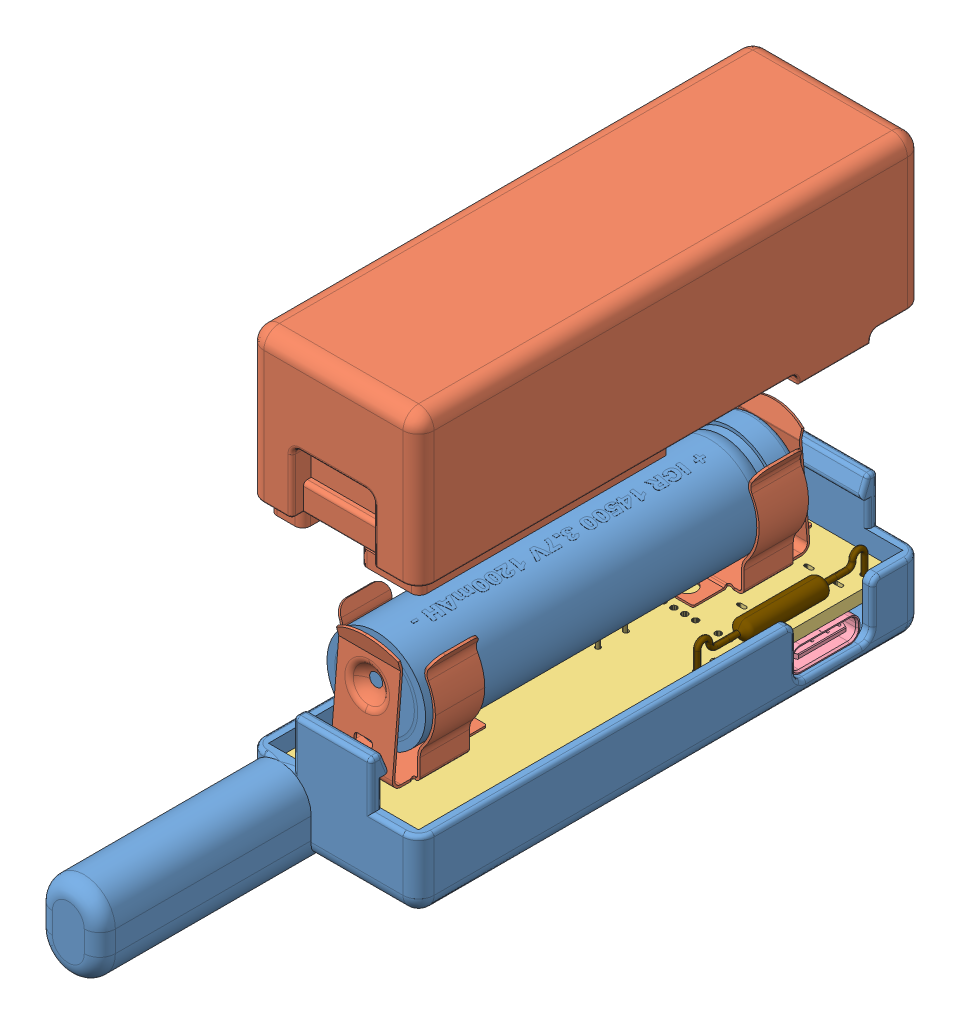
SolidWorks assembly Assem1, configuration Default. Lengths in mm.
Overall size (21.9 57.63 92.1).
106 component instances, 21 part files, 6 mates.
Components (placement in the parent):
- MailBoxGuard_Full_Size_Front_433_868_915-1: MailBoxGuard_Full_Size_Front_433_868_915 [Default] at (-14.6138 29.4677 86.179) size (21.9 16.85 92.1)
- MailBoxGuard_Full_Size_Back_433_868_915-1: MailBoxGuard_Full_Size_Back_433_868_915 [Default] at (-14.6138 81.2445 86.179) x (-1 0 0) z (0 0 1) size (21.9 21 64.9)
- MailBox_Guard_PCB.step-1: MailBox_Guard_PCB.step [Default] at (-22.3128 34.5477 64.4772) x (1 0 0) z (0 -1 0) size (19.9 77.28 23.81)
  - C_0603_1608Metric.step-1: C_0603_1608Metric.step [Default] at (9.97 33.512 1.63) size (1.6 0.8 0.8)
    - SOLID.step-1: SOLID.step [Default] at origin size (1.6 0.8 0.8)
  - C_0603_1608Metric.step-2: C_0603_1608Metric.step [Default] at (3.175 -0.651 1.63) x (0 1 0) z (0 0 1) size (1.6 0.8 0.8)
    - SOLID.step-1: SOLID.step [Default] at origin size (1.6 0.8 0.8)
  - UJC-HP-3-SMT-TR.step-1: UJC-HP-3-SMT-TR.step [Default] at (11.27 0.873 1.63) x (0 1 0) z (1 0 0) size (8.94 4.26 6.9)
    - COMPOUND.step-1: COMPOUND.step [Default] at origin size (8.94 4.26 6.9)
  - SOT-23.step-1: SOT-23.step [Default] at (14.732 18.907 1.63) x (0 1 0) z (0 0 1) size (2.5 3 1.2)
    - SOLID-0.step-1: SOLID-0.step [Default] at origin size (2.5 3 1.2)
  - D_SOD-323.step-1: D_SOD-323.step [Default] at (9.398 25.622 1.63) x (0 1 0) z (0 0 1) size (2.5 1.25 1.1)
    - SOLID-1.step-1: SOLID-1.step [Default] at origin size (2.5 1.25 1.1)
  - SOIJ-8_5.3x5.3mm_P1.27mm.step-1: SOIJ-8_5.3x5.3mm_P1.27mm.step [Default] at (6.985 0.873 1.63) x (0 -1 0) z (0 0 1) size (6.35 5.3 2.01)
    - SOLID-2.step-1: SOLID-2.step [Default] at origin size (6.35 5.3 2.01)
  - HTSOP-8-1EP_3.9x4.9mm_P1.27mm_EP2.4x3.2mm.step-1: HTSOP-8-1EP_3.9x4.9mm_P1.27mm_EP2.4x3.2mm.step [Default] at (6.985 0.873 1.63) x (0 -1 0) z (0 0 1) size (6.3 4.9 1.1)
    - SOLID-3.step-1: SOLID-3.step [Default] at origin size (6.3 4.9 1.1)
  - SOT-23.step-2: SOT-23.step [Default] at (6.415 24.3219 1.63) x (-1 0 0) z (0 0 1) size (2.5 3 1.2)
    - SOLID-0.step-1: SOLID-0.step [Default] at origin size (2.5 3 1.2)
  - D_SOD-323.step-2: D_SOD-323.step [Default] at (15.494 25.638 1.63) x (0 -1 0) z (0 0 1) size (2.5 1.25 1.1)
    - SOLID-1.step-1: SOLID-1.step [Default] at origin size (2.5 1.25 1.1)
  - R_0603_1608Metric.step-1: R_0603_1608Metric.step [Default] at (3.81 28.94 1.63) x (0 1 0) z (0 0 1) size (1.6 0.8 0.45)
    - SOLID-4.step-1: SOLID-4.step [Default] at origin size (1.6 0.8 0.45)
  - C_1206_3216Metric.step-1: C_1206_3216Metric.step [Default] at (1.778 32.037 1.63) x (0 -1 0) z (0 0 1) size (3.2 1.6 1.6)
    - SOLID-5.step-1: SOLID-5.step [Default] at origin size (3.2 1.6 1.6)
  - R_0603_1608Metric.step-2: R_0603_1608Metric.step [Default] at (11.43 22.463 1.63) x (0 -1 0) z (0 0 1) size (1.6 0.8 0.45)
    - SOLID-4.step-1: SOLID-4.step [Default] at origin size (1.6 0.8 0.45)
  - C_0603_1608Metric.step-3: C_0603_1608Metric.step [Default] at (-0.254 25.892 1.63) x (0 1 0) z (0 0 1) size (1.6 0.8 0.8)
    - SOLID.step-1: SOLID.step [Default] at origin size (1.6 0.8 0.8)
  - R_0603_1608Metric.step-3: R_0603_1608Metric.step [Default] at (11.557 -5.604 1.63) x (-1 0 0) z (0 0 1) size (1.6 0.8 0.45)
    - SOLID-4.step-1: SOLID-4.step [Default] at origin size (1.6 0.8 0.45)
  - C_0603_1608Metric.step-4: C_0603_1608Metric.step [Default] at (1.778 27.797 1.63) x (0 1 0) z (0 0 1) size (1.6 0.8 0.8)
    - SOLID.step-1: SOLID.step [Default] at origin size (1.6 0.8 0.8)
  - VQFN-20-1EP_3x3mm_P0.45mm_EP1.55x1.55mm.step-1: VQFN-20-1EP_3x3mm_P0.45mm_EP1.55x1.55mm.step [Default] at (14.351 30.375 1.63) x (0 -1 0) z (0 0 1) size (3 3 0.6)
    - SOLID-6.step-1: SOLID-6.step [Default] at origin size (3 3 0.6)
  - R_0603_1608Metric.step-4: R_0603_1608Metric.step [Default] at (9.97 28.94 1.63) x (-1 0 0) z (0 0 1) size (1.6 0.8 0.45)
    - SOLID-4.step-1: SOLID-4.step [Default] at origin size (1.6 0.8 0.45)
  - R_0603_1608Metric.step-5: R_0603_1608Metric.step [Default] at (9.97 31.988 1.63) size (1.6 0.8 0.45)
    - SOLID-4.step-1: SOLID-4.step [Default] at origin size (1.6 0.8 0.45)
  - R_0603_1608Metric.step-6: R_0603_1608Metric.step [Default] at (6.604 -3.953 1.63) size (1.6 0.8 0.45)
    - SOLID-4.step-1: SOLID-4.step [Default] at origin size (1.6 0.8 0.45)
  - R_0603_1608Metric.step-7: R_0603_1608Metric.step [Default] at (9.398 22.463 1.63) x (0 1 0) z (0 0 1) size (1.6 0.8 0.45)
    - SOLID-4.step-1: SOLID-4.step [Default] at origin size (1.6 0.8 0.45)
  - SOT-23.step-3: SOT-23.step [Default] at (2.4919 24.3211 1.63) size (2.5 3 1.2)
    - SOLID-0.step-1: SOLID-0.step [Default] at origin size (2.5 3 1.2)
  - SOT-23.step-4: SOT-23.step [Default] at (11.811 15.224 1.63) size (2.5 3 1.2)
    - SOLID-0.step-1: SOLID-0.step [Default] at origin size (2.5 3 1.2)
  - D_SOD-323.step-3: D_SOD-323.step [Default] at (13.462 25.638 1.63) x (0 -1 0) z (0 0 1) size (2.5 1.25 1.1)
    - SOLID-1.step-1: SOLID-1.step [Default] at origin size (2.5 1.25 1.1)
  - AS312 AM312 PIR.step-1: AS312 AM312 PIR.step [Default] at (4.826 17.248 1.63) x (0.707107 -0.707107 0) z (0 0 1) size (9.98 9.98 6.93)
    - SOLID-7.step-1: SOLID-7.step [Default] at origin size (9.98 9.98 6.93)
  - R_0603_1608Metric.step-8: R_0603_1608Metric.step [Default] at (11.43 17.764 1.63) x (-1 0 0) z (0 0 1) size (1.6 0.8 0.45)
    - SOLID-4.step-1: SOLID-4.step [Default] at origin size (1.6 0.8 0.45)
  - R_0603_1608Metric.step-9: R_0603_1608Metric.step [Default] at (13.462 22.463 1.63) x (0 -1 0) z (0 0 1) size (1.6 0.8 0.45)
    - SOLID-4.step-1: SOLID-4.step [Default] at origin size (1.6 0.8 0.45)
  - R_0603_1608Metric.step-10: R_0603_1608Metric.step [Default] at (7.43 5.572 1.63) size (1.6 0.8 0.45)
    - SOLID-4.step-1: SOLID-4.step [Default] at origin size (1.6 0.8 0.45)
  - C_0603_1608Metric.step-5: C_0603_1608Metric.step [Default] at (3.81 32.877 1.63) x (0 -1 0) z (0 0 1) size (1.6 0.8 0.8)
    - SOLID.step-1: SOLID.step [Default] at origin size (1.6 0.8 0.8)
  - C_0603_1608Metric.step-6: C_0603_1608Metric.step [Default] at (-0.254 22.844 1.63) x (0 -1 0) z (0 0 1) size (1.6 0.8 0.8)
    - SOLID.step-1: SOLID.step [Default] at origin size (1.6 0.8 0.8)
  - C_0603_1608Metric.step-7: C_0603_1608Metric.step [Default] at (13.335 33.512 1.63) size (1.6 0.8 0.8)
    - SOLID.step-1: SOLID.step [Default] at origin size (1.6 0.8 0.8)
  - R_0603_1608Metric.step-11: R_0603_1608Metric.step [Default] at (9.97 30.464 1.63) x (-1 0 0) z (0 0 1) size (1.6 0.8 0.45)
    - SOLID-4.step-1: SOLID-4.step [Default] at origin size (1.6 0.8 0.45)
  - R_0603_1608Metric.step-12: R_0603_1608Metric.step [Default] at (6.604 -5.731 1.63) size (1.6 0.8 0.45)
    - SOLID-4.step-1: SOLID-4.step [Default] at origin size (1.6 0.8 0.45)
  - D_SOD-323.step-4: D_SOD-323.step [Default] at (11.4315 25.6273 1.63) x (0 -1 0) z (0 0 1) size (2.5 1.25 1.1)
    - SOLID-1.step-1: SOLID-1.step [Default] at origin size (2.5 1.25 1.1)
  - R_0603_1608Metric.step-13: R_0603_1608Metric.step [Default] at (15.5181 22.428 1.63) x (0 1 0) z (0 0 1) size (1.6 0.8 0.45)
    - SOLID-4.step-1: SOLID-4.step [Default] at origin size (1.6 0.8 0.45)
  - C_0603_1608Metric.step-8: C_0603_1608Metric.step [Default] at (2.667 2.397 1.63) x (0 -1 0) z (0 0 1) size (1.6 0.8 0.8)
    - SOLID.step-1: SOLID.step [Default] at origin size (1.6 0.8 0.8)
  - LED_0603_1608Metric.step-1: LED_0603_1608Metric.step [Default] at (-0.254 29.829 1.63) x (0 1 0) z (0 0 1) size (1.6 0.8 1.1)
    - SOLID-8.step-1: SOLID-8.step [Default] at origin size (1.6 0.8 1.1)
  - PinHeader_1x02_P2.00mm_Vertical.step-1: PinHeader_1x02_P2.00mm_Vertical.step [Default] at (0 0 1.63) x (-1 0 0) z (0 0 1) size (2 4 8.8)
    - SOLID-9.step-1: SOLID-9.step [Default] at origin size (2 4 8.8)
  - C_0603_1608Metric.step-9: C_0603_1608Metric.step [Default] at (11.43 19.288 1.63) size (1.6 0.8 0.8)
    - SOLID.step-1: SOLID.step [Default] at origin size (1.6 0.8 0.8)
  - RA-01H--3DModel-STEP-1.step-1: RA-01H--3DModel-STEP-1.step [Default] at (7.7353 43.484 1.63) x (1 0 0) z (0 -1 0) size (16 3.4 17)
    - COMPOUND-10.step-1: COMPOUND-10.step [Default] at origin size (16 3.4 17)
  - SW868-TH13.step-1: SW868-TH13.step [Default] at (0.7353 55.984 4.13) x (0 0 -1) z (1 0 0) size (6.37 18.34 5.83)
    - SOLID-11.step-1: SOLID-11.step [Default] at origin size (6.37 18.34 5.83)
  - R_0603_1608Metric.step-14: R_0603_1608Metric.step [Default] at (11.557 7.223 1.63) x (-1 0 0) z (0 0 1) size (1.6 0.8 0.45)
    - SOLID-4.step-1: SOLID-4.step [Default] at origin size (1.6 0.8 0.45)
  - R_0603_1608Metric.step-15: R_0603_1608Metric.step [Default] at (7.43 7.096 1.63) size (1.6 0.8 0.45)
    - SOLID-4.step-1: SOLID-4.step [Default] at origin size (1.6 0.8 0.45)
  - LED_0603_1608Metric.step-2: LED_0603_1608Metric.step [Default] at (3.556 -5.731 1.63) x (-1 0 0) z (0 0 1) size (1.6 0.8 1.1)
    - SOLID-8.step-1: SOLID-8.step [Default] at origin size (1.6 0.8 1.1)
  - SOT-23.step-5: SOT-23.step [Default] at (6.4282 28.0545 1.63) size (2.5 3 1.2)
    - SOLID-0.step-1: SOLID-0.step [Default] at origin size (2.5 3 1.2)
  - LED_0603_1608Metric.step-3: LED_0603_1608Metric.step [Default] at (3.556 -3.953 1.63) x (-1 0 0) z (0 0 1) size (1.6 0.8 1.1)
    - SOLID-8.step-1: SOLID-8.step [Default] at origin size (1.6 0.8 1.1)
  - R_0603_1608Metric.step-16: R_0603_1608Metric.step [Default] at (-0.254 32.877 1.63) x (0 -1 0) z (0 0 1) size (1.6 0.8 0.45)
    - SOLID-4.step-1: SOLID-4.step [Default] at origin size (1.6 0.8 0.45)
  - SOT-23-5.step-1: SOT-23-5.step [Default] at (6.35 32.242 1.63) x (0 1 0) z (0 0 1) size (2.8 2.9 1.55)
    - SOLID-12.step-1: SOLID-12.step [Default] at origin size (2.8 2.9 1.55)
  - Reed switch1.step-1: Reed switch1.step [Default] at (15.621 16.802 -1.55) x (1 0 0) z (0 0 -1) size (2.7 22.13 6.72)
    - COMPOUND-13.step-1: COMPOUND-13.step [Default] at origin size (2.7 22.13 6.72)
  - ICR 14500.step-1: ICR 14500.step [Default] at (5.842 46.828 -8.85) x (1 0 0) z (0 -1 0) size (12.69 14.65 49.71)
    - SOLID-14.step-1: SOLID-14.step [Default] at origin size (12.69 14.65 49.71)
  - keystone-PN53TR.step-1: keystone-PN53TR.step [Default] at (5.842 -2.172 -0.55) x (1 0 0) z (0 1 0) size (13.31 15.64 16.8)
    - SOLID-15.step-1: SOLID-15.step [Default] at origin size (13.31 15.64 16.8)
  - keystone-PN53TR.step-2: keystone-PN53TR.step [Default] at (5.842 45.828 -0.55) x (-1 0 0) z (0 -1 0) size (13.31 15.64 16.8)
    - SOLID-15.step-1: SOLID-15.step [Default] at origin size (13.31 15.64 16.8)
  - PCB.step-1: PCB.step [Default] at origin size (18.8 61.18 1.58)
Mates (geometry in assembly coordinates):
- Coincident1: coincident anti-aligned: plane of MailBoxGuard_Full_Size_Front_868_915-1 through (-24.2638 36.4677 55.029) normal (1 0 0); plane of MailBoxGuard_Full_Size_Back_433_868_915-1 through (-24.2638 67.2445 56.529) normal (-1 0 0)
- Distance1: distance = 0.3 mm anti-aligned: plane of MailBox_Guard_PCB.step-1/PCB.step-1 through (-23.9638 34.5477 75.8014) normal (-1 0 0); plane of MailBoxGuard_Full_Size_Front_433_868_915-1 through (-24.2638 36.4677 55.029) normal (1 0 0)
- Distance2: distance = 0.7 mm anti-aligned: plane of MailBox_Guard_PCB.step-1/PCB.step-1 through (-5.9298 34.5477 55.729) normal (0 0 -1); plane of MailBoxGuard_Full_Size_Front_433_868_915-1 through (-24.2638 36.4677 55.029) normal (0 0 1)
- Coincident8: coincident anti-aligned: plane of MailBoxGuard_Full_Size_Front_433_868_915-1 through (-22.2638 32.9677 73.679) normal (0 1 0); plane of MailBox_Guard_PCB.step-1/PCB.step-1 through (-14.5605 32.9677 86.0719) normal (0 -1 0)
- Coincident9: coincident aligned: plane of MailBoxGuard_Full_Size_Front_433_868_915-1 through (-3.6638 36.4677 53.729) normal (1 0 0); plane of MailBoxGuard_Full_Size_Back_433_868_915-1 through (-3.6638 64.2445 86.179) normal (1 0 0)
- Coincident10: coincident aligned: plane of MailBoxGuard_Full_Size_Front_433_868_915-1 through (-25.5638 36.4677 53.729) normal (0 0 -1); plane of MailBoxGuard_Full_Size_Back_433_868_915-1 through (-14.6138 64.2445 53.729) normal (0 0 -1)
